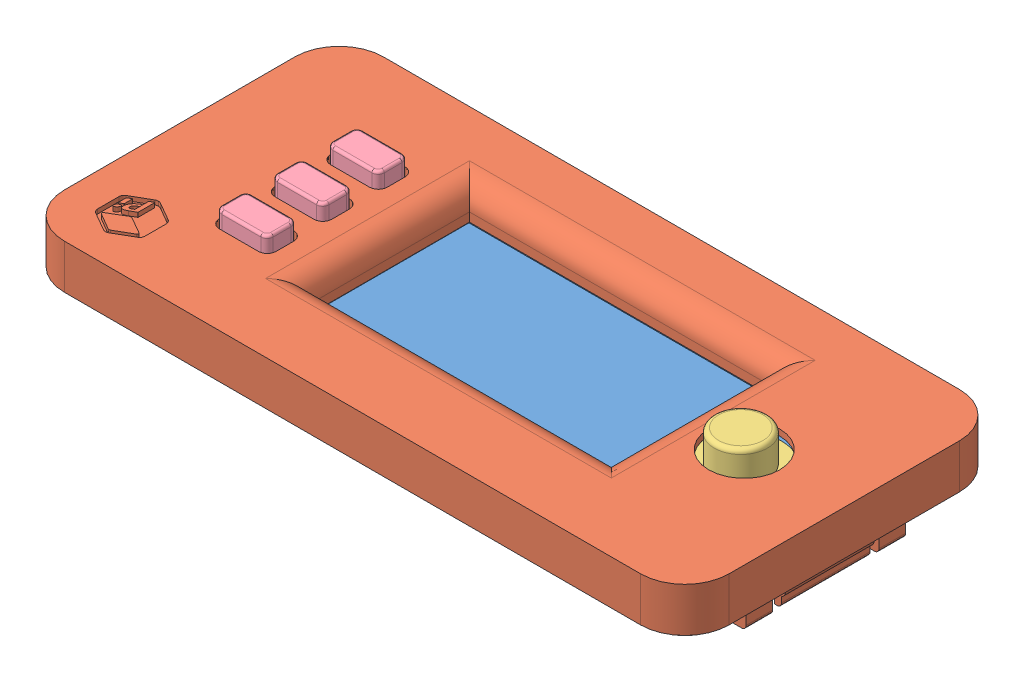
SolidWorks assembly 1.3inch_oled_comp, configuration 默认. Lengths in mm.
Overall size (75 13.13 36).
4 component instances, 4 part files, 0 mates.
Components (placement in the parent):
- 1.3inch_oled_hat-1: 1.3inch_oled_hat [默认] at (0.064 -0.0846 65) size (65 10.31 30.75)
- pisugar_case_oled_cap-1: pisugar_case_oled_cap [默认] at (0.0693 7.1287 65.0201) x (1 0 0) z (0 0 -1) size (75 8.6 36)
- pisugar_case_oled_handle-1: pisugar_case_oled_handle [默认] at (24.6549 9.3697 65.3301) x (1 0 0) z (0 0 -1) size (9 4.3 9)
- pisugar_case_oled_button-1: pisugar_case_oled_button [默认] at (-24.2599 8.6603 70.6147) x (-1 0 0) z (0 0 1) size (11.85 4 20)
